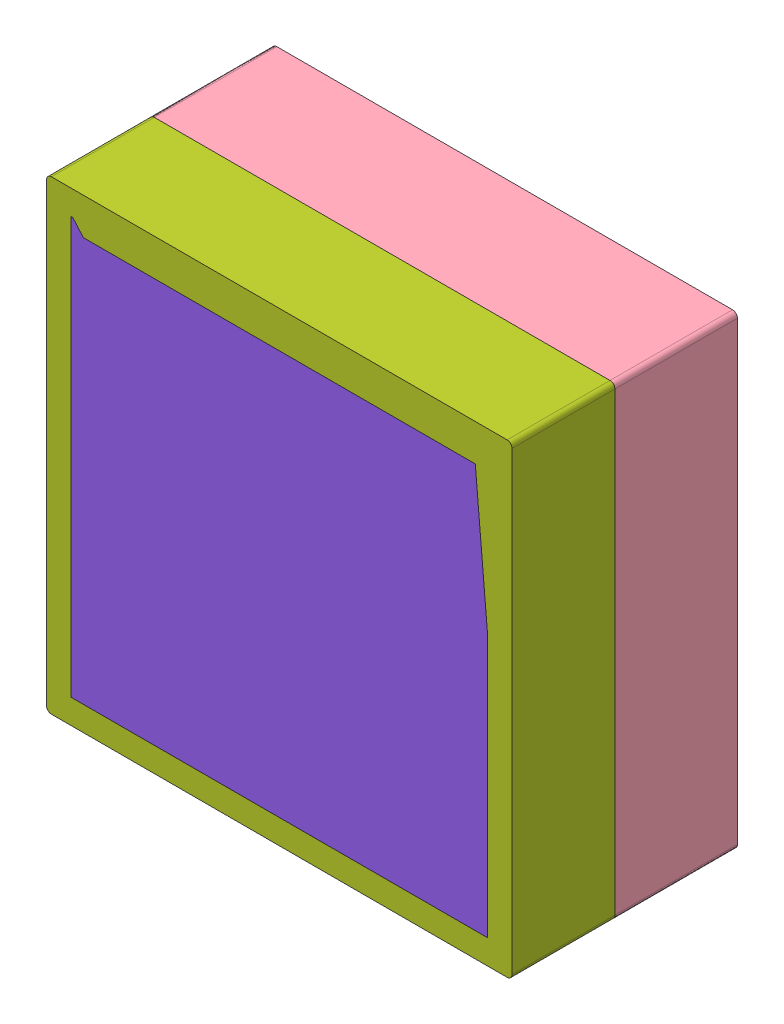
SolidWorks assembly ITEMS Assembly, configuration Default. Lengths in mm.
Overall size (95 95 46).
20 component instances, 8 part files, 26 mates.
Components (placement in the parent):
- ITEMS PCBA-1: ITEMS PCBA [Default] at (-5.0871 -0.3105 7.8309) x (1 0.000955 0) z (0 0 1) size (90.14 89.28 37.06)
  - ITEMS PCB Rev A-1: ITEMS PCB Rev A [Default] at (-72.5391 -40.3839 12.7465) size (90.14 89.28 37.06)
  - A_GPS_main-1: A_GPS_main [Default] at (23.7514 13.1728 20.502) x (0 1 0) z (-1 0 0) size (35.6 12.33 26.08)
  - 4-Pin Header - Male - 2.54mm.step-1: 4-Pin Header - Male - 2.54mm.step [Default] at (5.3079 30.6891 20.2865) x (-1 0 0) z (0 0 -1) size (10.16 2.54 11.94)
    - 4-Pin Header - Male - 2.54mm.step-1: 4-Pin Header - Male - 2.54mm.step [Default] x (1 0 0) z (0 -1 0) size (10.16 11.94 2.54)
- ITEMS Bottom Case-1: ITEMS Bottom Case [Default] at (-32.7479 4.475 0) x (1 0 0) z (0 -1 0) size (95 27 95)
- 94459A140_Heat-Set Inserts for Plastic (1)-1: 94459A140_Heat-Set Inserts for Plastic (1) [94459A140] at (7.1521 44.575 16.3) x (-0.923728 -0.383049 0) z (-0.383049 0.923728 0) size (4.76 5.79 4.76)
- 94459A140_Heat-Set Inserts for Plastic (1)-2: 94459A140_Heat-Set Inserts for Plastic (1) [94459A140] at (-72.8479 44.575 16.3) x (-0.85131 -0.524663 0) z (-0.524663 0.85131 0) size (4.76 5.79 4.76)
- 94459A140_Heat-Set Inserts for Plastic (1)-3: 94459A140_Heat-Set Inserts for Plastic (1) [94459A140] at (-72.8479 -35.625 16.3) x (-0.777574 -0.628792 0) z (-0.628792 0.777574 0) size (4.76 5.79 4.76)
- 94459A140_Heat-Set Inserts for Plastic (1)-4: 94459A140_Heat-Set Inserts for Plastic (1) [94459A140] at (7.1521 -35.625 16.3) x (-0.715577 -0.698533 0) z (-0.698533 0.715577 0) size (4.76 5.79 4.76)
- 91290A111_Alloy Steel Socket Head Screw-1: 91290A111_Alloy Steel Socket Head Screw [91290A111] at (-72.6687 44.2411 19.0673) x (0.999886 -0.015088 0) z (0 0 1) size (5.5 5.5 9.19)
- 91290A111_Alloy Steel Socket Head Screw-2: 91290A111_Alloy Steel Socket Head Screw [91290A111] at (7.3312 44.3174 19.0673) x (0.98963 0.143637 0) z (0 0 1) size (5.5 5.5 9.19)
- 91290A111_Alloy Steel Socket Head Screw-3: 91290A111_Alloy Steel Socket Head Screw [91290A111] at (7.4076 -35.6825 19.0673) x (0.963285 0.26848 0) z (0 0 1) size (5.5 5.5 9.19)
- 91290A111_Alloy Steel Socket Head Screw-4: 91290A111_Alloy Steel Socket Head Screw [91290A111] at (-72.5454 -35.7589 19.0673) x (0.934066 0.357101 0) z (0 0 1) size (5.5 5.5 9.19)
- 94459A140_Heat-Set Inserts for Plastic (1)-6: 94459A140_Heat-Set Inserts for Plastic (1) [94459A140] at (5.9421 30.845 14.3) x (-0.938752 -0.344593 0) z (-0.344593 0.938752 0) size (4.76 5.79 4.76)
- 94459A140_Heat-Set Inserts for Plastic (1)-7: 94459A140_Heat-Set Inserts for Plastic (1) [94459A140] at (-14.0579 30.845 14.3) x (-0.85131 -0.524663 0) z (-0.524663 0.85131 0) size (4.76 5.79 4.76)
- 94459A140_Heat-Set Inserts for Plastic (1)-9: 94459A140_Heat-Set Inserts for Plastic (1) [94459A140] at (5.9421 0.845 14.3) x (-0.461845 -0.88696 0) z (-0.88696 0.461845 0) size (4.76 5.79 4.76)
- 94459A140_Heat-Set Inserts for Plastic (1)-11: 94459A140_Heat-Set Inserts for Plastic (1) [94459A140] at (-14.0579 0.845 14.3) x (-0.123494 -0.992345 0) z (-0.992345 0.123494 0) size (4.76 5.79 4.76)
- ITEMS Top Case-1: ITEMS Top Case [Default] at (-32.7479 4.475 46) x (0 -1 0) z (1 0 0) size (95 21 95)
- Plexiglass Cutout 85mm squared-1: Plexiglass Cutout 85mm squared [Default] at (-32.7479 4.475 43) x (1 0 0) z (0 -1 0) size (85 3 85)
Mates (geometry in assembly coordinates):
- Coincident1: coincident anti-aligned: plane of ITEMS Bottom Case-1 through (-32.7479 4.475 0) normal (0 0 -1)
- Coincident2: coincident anti-aligned: plane of ITEMS PCBA-1/ITEMS PCB Rev A-1 through (-33.1894 4.6737 20) normal (0 0 -1); plane of ITEMS Bottom Case-1 through (-73.2479 44.975 20) normal (0 0 1)
- Coincident3: coincident: plane of ITEMS Bottom Case-1 through (7.2521 44.475 22) normal (0 0 1); plane of 94459A140_Heat-Set Inserts for Plastic (1)-1 through (4.9813 43.6748 22) normal (0 0 1)
- Coincident4: coincident: plane of ITEMS Bottom Case-1 through (7.2521 44.475 22) normal (0 0 1); plane of 94459A140_Heat-Set Inserts for Plastic (1)-2 through (-74.8485 43.342 22) normal (0 0 1)
- Coincident5: coincident: plane of ITEMS Bottom Case-1 through (7.2521 44.475 22) normal (0 0 1); plane of 94459A140_Heat-Set Inserts for Plastic (1)-3 through (-74.6752 -37.1027 22) normal (0 0 1)
- Coincident6: coincident: plane of ITEMS Bottom Case-1 through (7.2521 44.475 22) normal (0 0 1); plane of 94459A140_Heat-Set Inserts for Plastic (1)-4 through (5.4705 -37.2666 22) normal (0 0 1)
- Coincident8: coincident anti-aligned: plane of ITEMS PCBA-1/ITEMS PCB Rev A-1 through (-40.692 -7.5786 20.5673) normal (0 0 1); plane of 91290A111_Alloy Steel Socket Head Screw-1 through (-75.2684 44.2803 20.5673) normal (0 0 -1)
- Concentric10: concentric anti-aligned: circle of ITEMS PCBA-1/ITEMS PCB Rev A-1; circle of 91290A111_Alloy Steel Socket Head Screw-1
- Coincident9: coincident anti-aligned: plane of ITEMS PCBA-1/ITEMS PCB Rev A-1 through (-40.692 -7.5786 20.5673) normal (0 0 1); plane of 91290A111_Alloy Steel Socket Head Screw-2 through (4.7582 43.944 20.5673) normal (0 0 -1)
- Concentric11: concentric anti-aligned: circle of ITEMS PCBA-1/ITEMS PCB Rev A-1; circle of 91290A111_Alloy Steel Socket Head Screw-2
- Coincident10: coincident anti-aligned: plane of ITEMS PCBA-1/ITEMS PCB Rev A-1 through (-40.692 -7.5786 20.5673) normal (0 0 1); plane of 91290A111_Alloy Steel Socket Head Screw-3 through (4.903 -36.3806 20.5673) normal (0 0 -1)
- Concentric12: concentric anti-aligned: circle of ITEMS PCBA-1/ITEMS PCB Rev A-1; circle of 91290A111_Alloy Steel Socket Head Screw-3
- Coincident11: coincident anti-aligned: plane of ITEMS PCBA-1/ITEMS PCB Rev A-1 through (-40.692 -7.5786 20.5673) normal (0 0 1); plane of 91290A111_Alloy Steel Socket Head Screw-4 through (-74.9739 -36.6873 20.5673) normal (0 0 -1)
- Concentric13: concentric anti-aligned: circle of ITEMS PCBA-1/ITEMS PCB Rev A-1; circle of 91290A111_Alloy Steel Socket Head Screw-4
- Coincident13: coincident aligned: plane of ITEMS Bottom Case-1 through (7.7521 44.975 20) normal (0 0 1); plane of 94459A140_Heat-Set Inserts for Plastic (1)-6 through (3.736 30.0352 20) normal (0 0 1)
- Concentric14: concentric aligned: circle of ITEMS Bottom Case-1; circle of 94459A140_Heat-Set Inserts for Plastic (1)-6
- Coincident14: coincident aligned: plane of ITEMS Bottom Case-1 through (7.7521 44.975 20) normal (0 0 1); plane of 94459A140_Heat-Set Inserts for Plastic (1)-7 through (-16.0585 29.612 20) normal (0 0 1)
- Coincident16: coincident aligned: plane of ITEMS Bottom Case-1 through (7.7521 44.975 20) normal (0 0 1); plane of 94459A140_Heat-Set Inserts for Plastic (1)-9 through (4.8567 -1.2394 20) normal (0 0 1)
- Concentric17: concentric aligned: circle of ITEMS Bottom Case-1; circle of 94459A140_Heat-Set Inserts for Plastic (1)-9
- Concentric18: concentric aligned: circle of ITEMS Bottom Case-1; circle of 94459A140_Heat-Set Inserts for Plastic (1)-7
- Coincident18: coincident aligned: plane of ITEMS Bottom Case-1 through (7.7521 44.975 20) normal (0 0 1); plane of 94459A140_Heat-Set Inserts for Plastic (1)-7 through (-16.0585 29.612 20) normal (0 0 1)
- Coincident19: coincident aligned: plane of ITEMS Bottom Case-1 through (7.7521 44.975 20) normal (0 0 1); plane of 94459A140_Heat-Set Inserts for Plastic (1)-11 through (-14.3482 -1.487 20) normal (0 0 1)
- Concentric19: concentric aligned: circle of ITEMS Bottom Case-1; circle of 94459A140_Heat-Set Inserts for Plastic (1)-11
- Coincident21: coincident anti-aligned: plane of ITEMS Bottom Case-1 through (13.7521 -42.025 25) normal (0 0 1); plane of ITEMS Top Case-1 through (-79.2479 -42.025 25) normal (0 0 -1)
- Coincident22: coincident aligned: plane of ITEMS Bottom Case-1 through (-80.2479 -43.025 2) normal (0 -1 0); plane of ITEMS Top Case-1 through (13.7521 -43.025 42) normal (0 -1 0)
- Coincident23: coincident aligned: plane of ITEMS Bottom Case-1 through (-80.2479 -43.025 2) normal (-1 0 0); plane of ITEMS Top Case-1 through (-80.2479 50.975 42) normal (-1 0 0)
